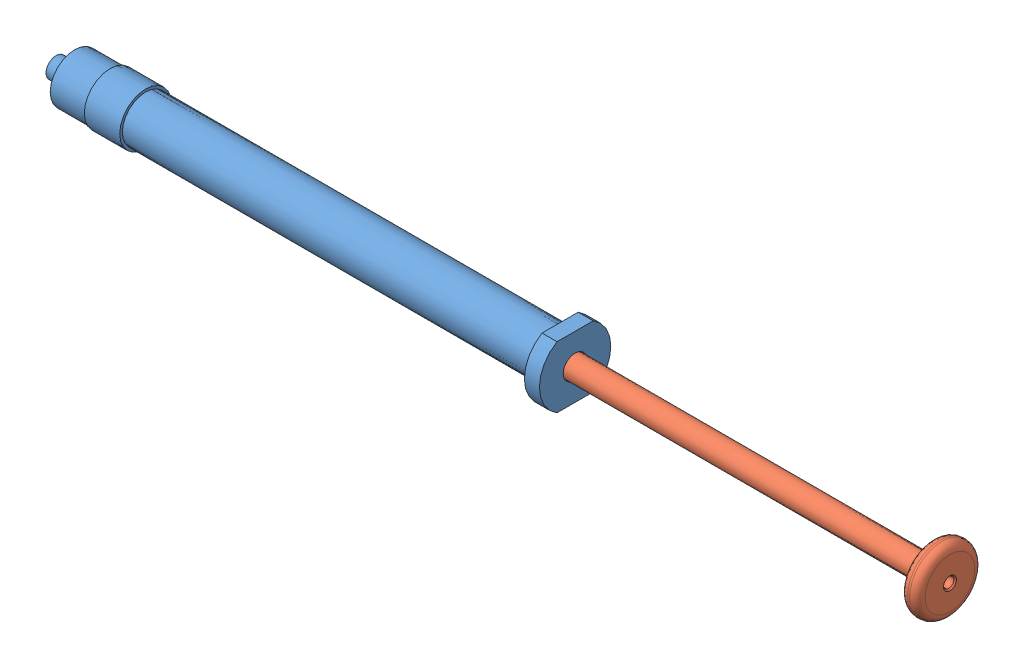
SolidWorks assembly 1Mililiter_Hamilton_Syringe_Asmbly, configuration Default. Lengths in mm.
Overall size (172.74 16.41 16.41).
2 component instances, 2 part files, 1 mates.
Components (placement in the parent):
- Hamilton_1mililiter_Syringe-1: Hamilton_1mililiter_Syringe [Default] at (33.1763 54.2911 77.9142) size (100.3 11.9 13.8)
- 1ml_Plunger-1: 1ml_Plunger [Default] at (104.9664 54.2911 77.9142) x (1 0 0) z (0 -0.926675 -0.375864) size (101.6 12.6 12.6)
Mates (geometry in assembly coordinates):
- Concentric1: concentric anti-aligned: circle of Hamilton_1mililiter_Syringe-1; cylinder of 1ml_Plunger-1 through (54.1664 54.2911 77.9142) axis (-1 0 0) radius 2.335
